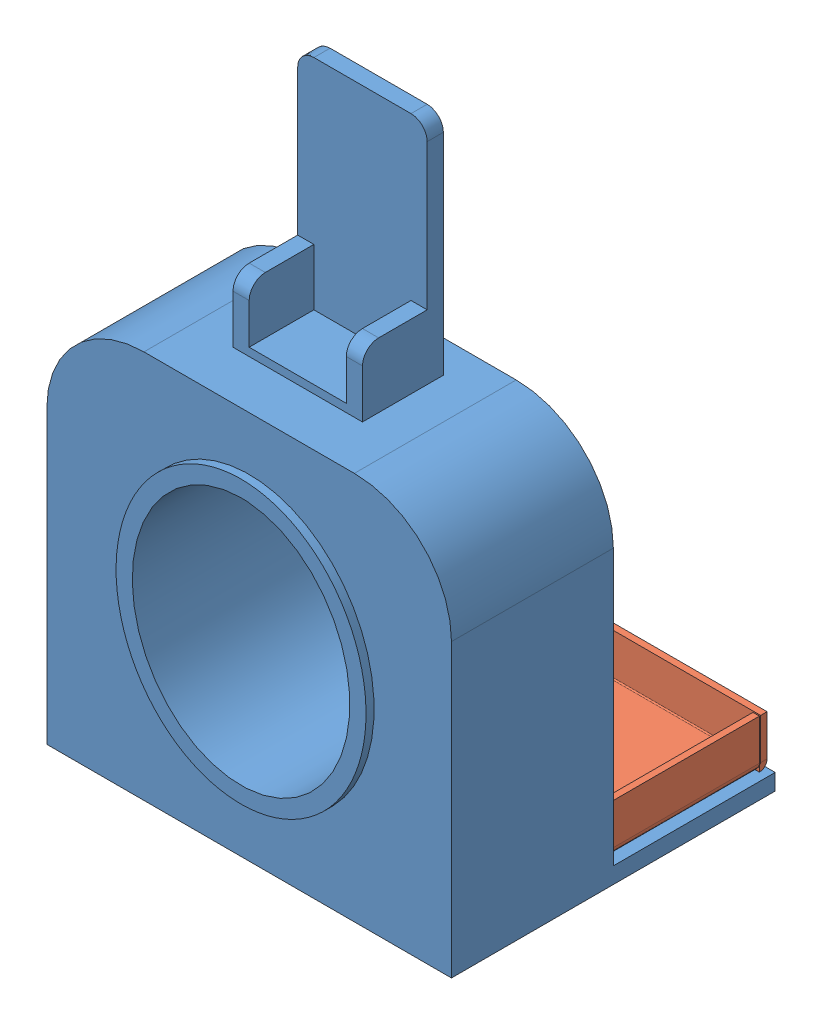
SolidWorks assembly Ensamble proyecto, configuration Default. Lengths in mm.
Overall size (250 380 205.01).
2 component instances, 2 part files, 6 mates.
Components (placement in the parent):
- RedesParte1-1: RedesParte1 [Default] at origin size (250 380 205.01)
- RedesParte2-1: RedesParte2 [Default] at (5 10 -100) size (240 30 100)
Mates (geometry in assembly coordinates):
- Coincidente1: coincident: plane of RedesParte1-1 through (0 240 -100) normal (0 0 -1); plane of RedesParte2.0-1 through (10 40 -100) normal (0 0 1)
- Coincidente2: coincident: plane of RedesParte1-1 through (0 10 0) normal (0 1 0); plane of RedesParte2.0-1 through (10 10 -100) normal (0 -1 0)
- Distancia1: distance = 5 mm aligned: plane of RedesParte2.0-1 through (245 40 -100) normal (1 0 0); plane of RedesParte1-1 through (250 240 0) normal (1 0 0)
- Coincidente3: coincident anti-aligned: plane of RedesParte1-1 through (0 240 -100) normal (0 0 -1); plane of RedesParte2-1 through (5 10 -100) normal (0 0 1)
- Coincidente4: coincident anti-aligned: plane of RedesParte1-1 through (0 10 0) normal (0 1 0); plane of RedesParte2-1 through (5 10 -100) normal (0 -1 0)
- Distancia3: distance = 5 mm aligned: plane of RedesParte2-1 through (245 10 -100) normal (1 0 0); plane of RedesParte1-1 through (250 240 0) normal (1 0 0)
